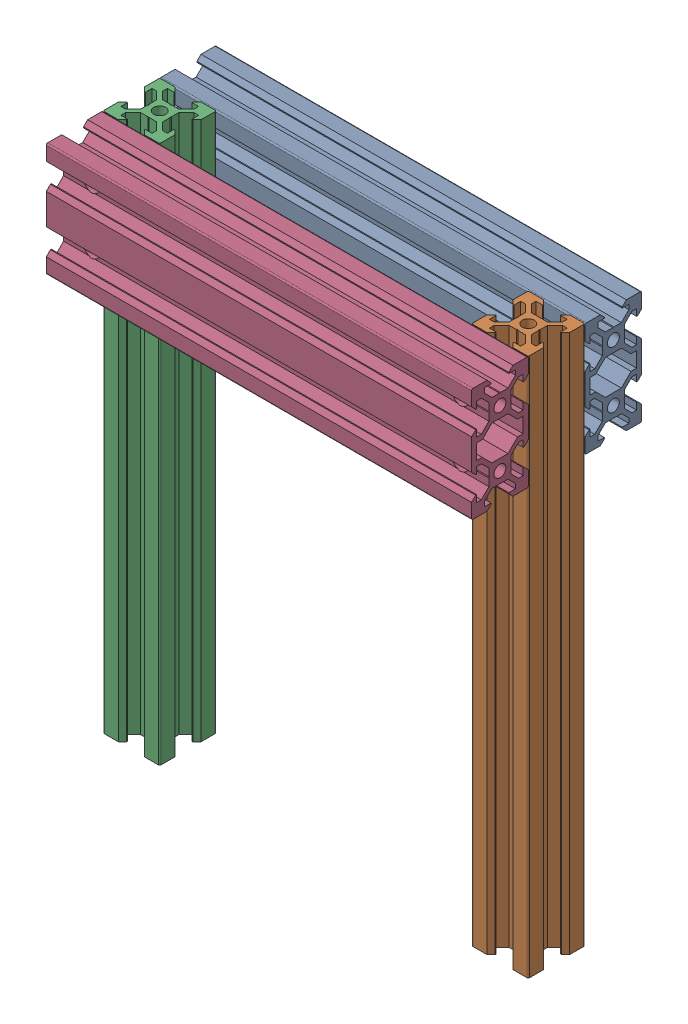
SolidWorks assembly Aft Frame Assembly, configuration Default. Lengths in mm.
Overall size (150 190 60).
4 component instances, 2 part files, 0 mates.
Components (placement in the parent):
- V-Slot 20x40x150 Linear Rail-1: V-Slot 20x40x150 Linear Rail [Default] at (-75 75 10) x (0 0 -1) z (1 0 0) size (20 40 150)
- V-Slot 20x20x190 Linear Rail Tapped Ends-1: V-Slot 20x20x190 Linear Rail Tapped Ends [Default] at (65 95 30) x (1 0 0) z (0 -1 0) size (20 20 190)
- V-Slot 20x20x190 Linear Rail Tapped Ends-2: V-Slot 20x20x190 Linear Rail Tapped Ends [Default] at (-65 95 30) x (1 0 0) z (0 -1 0) size (20 20 190)
- V-Slot 20x40x150 Linear Rail-2: V-Slot 20x40x150 Linear Rail [Default] at (-75 75 50) x (0 0 -1) z (1 0 0) size (20 40 150)
